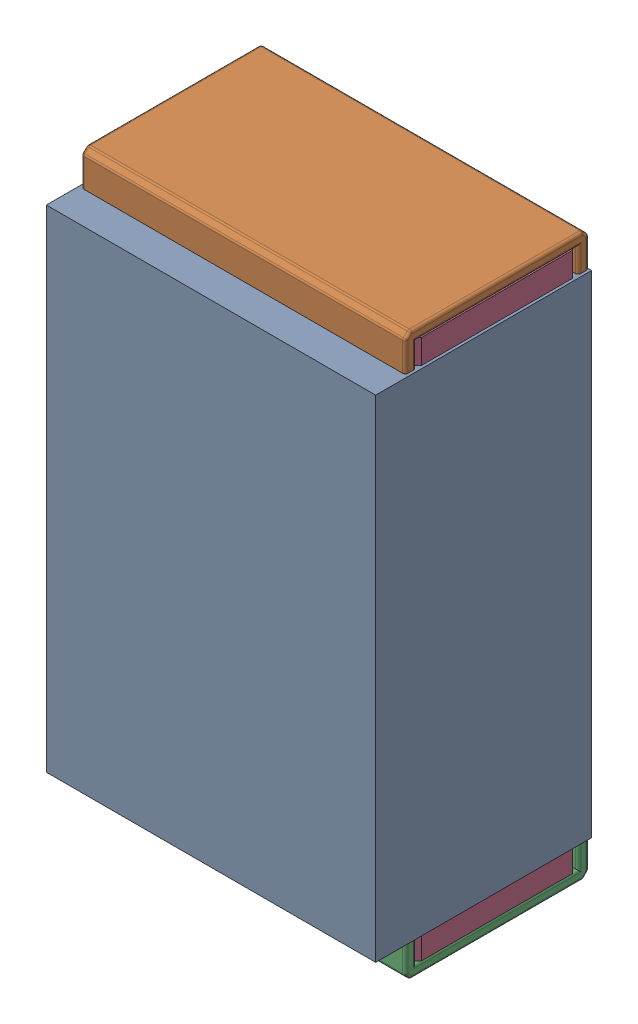
SolidWorks assembly R7, configuration Default. Lengths in mm.
Overall size (0.61 1.04 0.4).
3 component instances, 2 part files, 0 mates.
Components (placement in the parent):
- 1088881848-1: 1088881848 [Default] at (14.95 38.6 0) size (0.61 0.91 0.4)
  - Extruded-1-1: Extruded-1 [Default] at origin size (0.61 0.91 0.4)
- R0402-1: R0402 [Default] at (14.9499 38.6 0) x (0 1 0) z (1 0 0) size (1.04 0.34 0.6)
